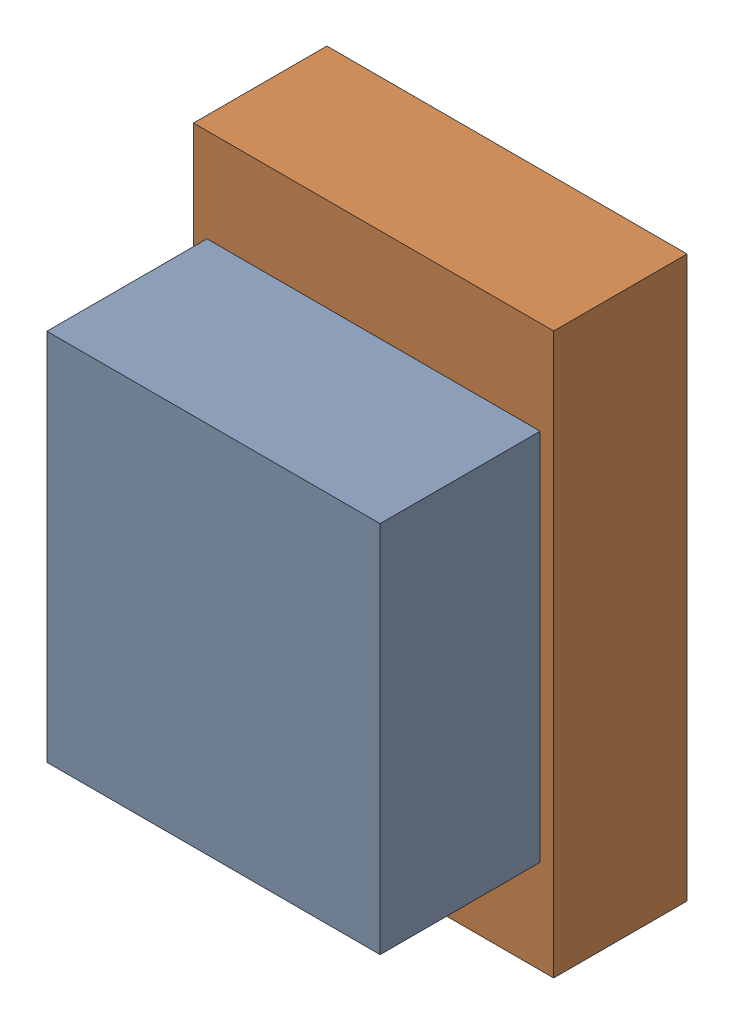
SolidWorks assembly D2, configuration Default. Lengths in mm.
Overall size (1.35 2.1 1.1).
4 component instances, 2 part files, 0 mates.
Components (placement in the parent):
- 6638392528-1: 6638392528 [Default] at (1.651 9.017 0.5) size (1.25 1.4 0.6)
  - Extruded_14-1: Extruded_14 [Default] at origin size (1.25 1.4 0.6)
- 6638392368-1: 6638392368 [Default] at (1.651 9.017 0) size (1.35 2.1 0.5)
  - Extruded_15-1: Extruded_15 [Default] at origin size (1.35 2.1 0.5)
